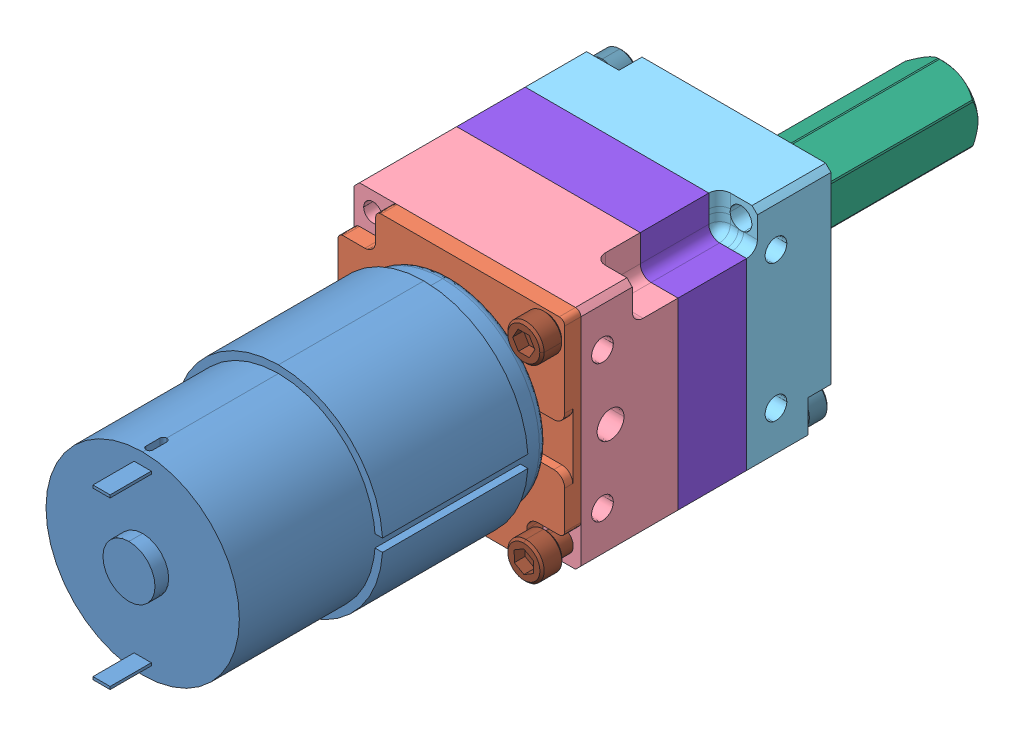
SolidWorks assembly VersaPlanetary_v1_Single_Stage_10_1_with_RS_550, configuration Default. Lengths in mm.
Overall size (42.53 42 155.97).
32 component instances, 20 part files, 0 mates.
Components (placement in the parent):
- VersaPlanetary_v1_Single_Stage_10_1_with_RS_550.STEP-1: VersaPlanetary_v1_Single_Stage_10_1_with_RS_550.STEP [Default] at origin size (42.53 42 155.97)
  - 217-2625-100.STEP-1: 217-2625-100.STEP [Default] at (0 0 -18.467) x (0 1 0) z (0 0 1) size (39.22 38.88 12.7)
    - 217-2625-008 Rev1.STEP-1: 217-2625-008 Rev1.STEP [Default] at origin size (34.7 34.7 4.7)
    - 217-2625-010 Rev1.STEP-1: 217-2625-010 Rev1.STEP [Default] at (0 10.193 3.65) x (0.999813 0.019336 0) z (0 0 1) size (4 4 12)
    - 217-2625-010 Rev1.STEP-2: 217-2625-010 Rev1.STEP [Default] at (8.691 -5.3258 3.65) size (4 4 12)
    - 217-2625-010 Rev1.STEP-3: 217-2625-010 Rev1.STEP [Default] at (-8.691 -5.3258 3.65) size (4 4 12)
    - 217-2625-005 Rev1_Planet_Revolving_Follower01.STEP-1: 217-2625-005 Rev1_Planet_Revolving_Follower01.STEP [Default] at (8.691 -5.3258 6.35) x (0.932816 0.360354 0) z (0 0 1) size (16.89 16.89 8)
    - 217-2625-005 Rev1_Planet_Revolving_Follower01.STEP-2: 217-2625-005 Rev1_Planet_Revolving_Follower01.STEP [Default] at (-8.691 -5.3258 6.35) x (-0.932788 -0.360426 0) z (0 0 1) size (16.89 16.89 8)
    - 217-2625-005 Rev1_Planet_Revolving_Follower01.STEP-3: 217-2625-005 Rev1_Planet_Revolving_Follower01.STEP [Default] at (0 10.193 6.35) x (0.893583 0.448898 0) z (0 0 1) size (16.89 16.89 8)
  - 217-2625-001 Rev1.STEP-1: 217-2625-001 Rev1.STEP [Default] at origin size (42 42 18)
  - 217-2625-002 Rev1.STEP-1: 217-2625-002 Rev1.STEP [Default] at (0 0 -16.7) size (42 42 17.12)
  - 217-2625-003 Rev1.STEP-1: 217-2625-003 Rev1.STEP [Default] at (0 0 -30.9478) x (1 0 0) z (0 0 -1) size (17 17 64.11)
  - 217-2625-009 Rev1.STEP-1: 217-2625-009 Rev1.STEP [Default] at (0 0 -3.48) x (0 -1 0) z (0 0 -1) size (18 18 13)
  - 217-2816-001 Rev1.STEP-1: 217-2816-001 Rev1.STEP [Default] at (0 0 -16.85) x (1 0 0) z (0 0 -1) size (42 42 14.51)
  - 217-2625-007 Rev1_Sun_Driver01.STEP-1: 217-2625-007 Rev1_Sun_Driver01.STEP [Default] at (0 0 -11.767) x (0.055822 0.998441 0) z (0 0 1) size (15.27 15.27 12.71)
  - 217-2625-012 Rev1.STEP-1: 217-2625-012 Rev1.STEP [Default] at (0 0 -2.4942) size (8.01 7.94 7.5)
  - SSA_SSA0832-0500ZC.STEP-1: SSA_SSA0832-0500ZC.STEP [Default] at (-17.4921 -17.5079 10.5) x (0.008716 -0.999962 0) z (-0.999962 -0.008716 0) size (6.73 16.76 6.73)
  - SSA_SSAM3-0008ZC.STEP-1: SSA_SSAM3-0008ZC.STEP [Default] at (0 12.5 17.025) x (-0.999994 -0.00359 0) z (0.00359 -0.999994 0) size (5.5 11 5.5)
  - SSA_SSAM3-0008ZC.STEP-2: SSA_SSAM3-0008ZC.STEP [Default] at (0 -12.5 17.025) x (-0.960339 -0.278833 0) z (0.278833 -0.960339 0) size (5.5 11 5.5)
  - 217-2742.STEP-1: 217-2742.STEP [Default] at (0 0 -30.4002) x (0 0 1) z (-1 0 0) size (7 28 28)
  - 217-2742.STEP-2: 217-2742.STEP [Default] at (0 0 -38.7002) x (0 0 1) z (-0.997393 0.072165 0) size (7 28 28)
  - SSA_SSA0832-1250ZC.STEP-1: SSA_SSA0832-1250ZC.STEP [Default] at (17.5 -17.5 -34.561) x (1 0 0) z (0 1 0) size (6.73 35.81 6.73)
  - SSA_SSA0832-1250ZC.STEP-2: SSA_SSA0832-1250ZC.STEP [Default] at (-17.5 17.5 -34.561) x (1 0 0) z (0 1 0) size (6.73 35.81 6.73)
  - SSS1032-0125ZB_94105A824.STEP-1: SSS1032-0125ZB_94105A824.STEP [Default] at (-6.908 0 1.995) x (0 -0.92485 0.380331) z (-1 0 0) size (4.84 4.84 3.18)
  - 217-2625-018 Rev1_98541A410.STEP-1: 217-2625-018 Rev1_98541A410.STEP [Default] at (0 0 -22.7954) x (0 0 -1) z (0.980859 -0.194721 0) size (1 19.6 17.4)
  - 217-2625-017 Rev1_9714K61.STEP-1: 217-2625-017 Rev1_9714K61.STEP [Default] at (0 0 -31.4002) x (-0.695225 0.718792 0) z (-0.718792 -0.695225 0) size (28.51 4.98 27.43)
  - PINL-M020-006-S.STEP-1: PINL-M020-006-S.STEP [Default] at (-18.5 13.6657 -9.5) x (0 0 -1) z (1 0 0) size (6 2 2)
  - PINL-M020-006-S.STEP-2: PINL-M020-006-S.STEP [Default] at (-18.5 13.6657 -22.2) x (0 0 -1) z (0.23951 -0.970894 0) size (6 2 2)
  - BaneBots RS550.STEP-1: BaneBots RS550.STEP [Default] at (0 0 60.538) x (0 1 0) z (0 0 -1) size (38.61 38.57 77.9)
  - SSA_SSA0832-0500ZC.STEP-2: SSA_SSA0832-0500ZC.STEP [Default] at (17.5079 -17.4921 10.5) x (0.999962 0.008716 0) z (0.008716 -0.999962 0) size (6.73 16.76 6.73)
  - SSA_SSA0832-0500ZC.STEP-3: SSA_SSA0832-0500ZC.STEP [Default] at (17.4921 17.5079 10.5) x (-0.008716 0.999962 0) z (0.999962 0.008716 0) size (6.73 16.76 6.73)
  - 217-2822-001 Rev4.STEP-1: 217-2822-001 Rev4.STEP [Default] at (0 0 9) size (42 42 4.8)
